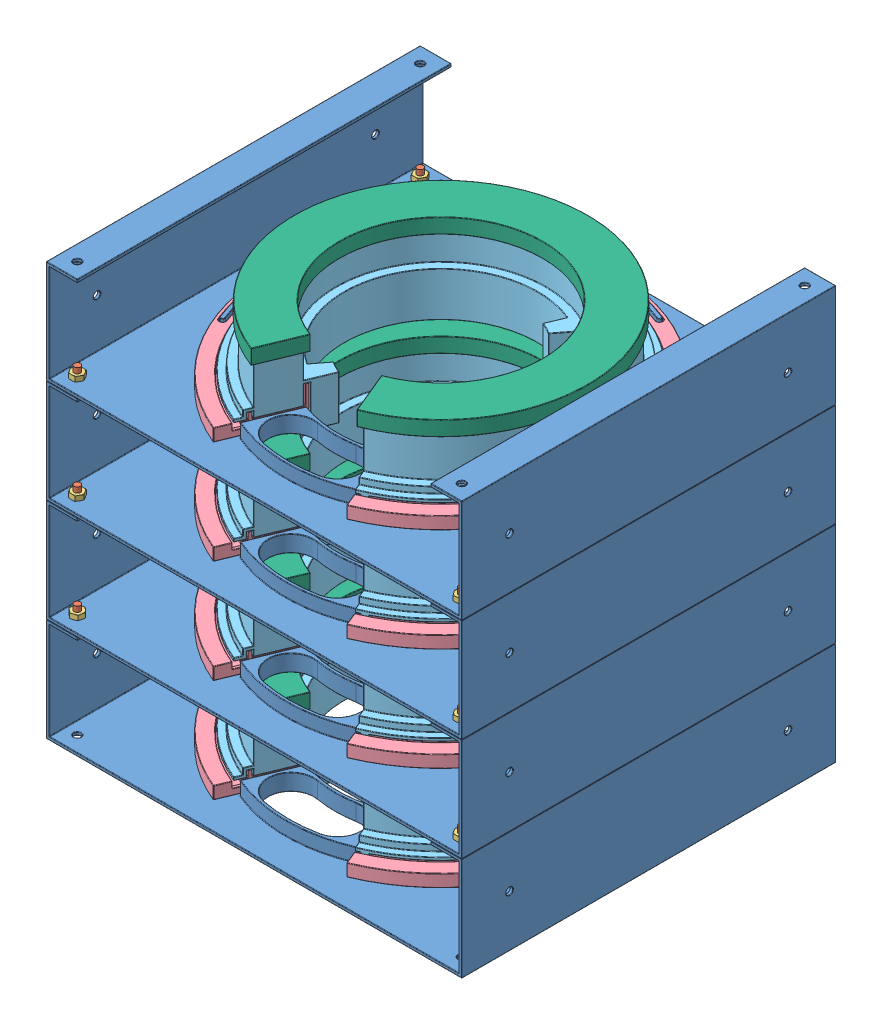
SolidWorks assembly Gavetas, configuration Valor predeterminado. Lengths in mm.
Overall size (200 201.3 180).
44 component instances, 6 part files, 69 mates.
Components (placement in the parent):
- CD-Gaveta-1: CD-Gaveta [Valor predeterminado] at (171.1976 -7.978 102.2527) x (1 0 0) z (0 1 0) size (200 180 49.7)
- CD-Gaveta-2: CD-Gaveta [Valor predeterminado] at (171.1976 41.722 102.2527) x (1 0 0) z (0 1 0) size (200 180 49.7)
- CD-Gaveta-3: CD-Gaveta [Valor predeterminado] at (171.1976 91.422 102.2527) x (1 0 0) z (0 1 0) size (200 180 49.7)
- CD-Gaveta-4: CD-Gaveta [Valor predeterminado] at (171.1976 141.122 102.2527) x (1 0 0) z (0 1 0) size (200 180 49.7)
- M3x8-1: M3x8 [Default] at (263.6976 89.922 184.7527) x (0 1 0) z (1 0 0) size (10.37 5.6 5.6)
- M3x8-2: M3x8 [Default] at (263.6976 89.922 19.7527) x (0 1 0) z (0 0 1) size (10.37 5.6 5.6)
- M3x8-3: M3x8 [Default] at (78.6976 40.222 184.7527) x (0 1 0) z (0 0 1) size (10.37 5.6 5.6)
- M3x8-4: M3x8 [Default] at (78.6976 89.922 184.7527) x (0 1 0) z (0 0 1) size (10.37 5.6 5.6)
- M3x8-5: M3x8 [Default] at (78.6976 89.922 19.7527) x (0 1 0) z (0 0 1) size (10.37 5.6 5.6)
- M3x8-6: M3x8 [Default] at (263.6976 40.222 19.7527) x (0 1 0) z (0 0 1) size (10.37 5.6 5.6)
- M3x8-7: M3x8 [Default] at (78.6976 40.222 19.7527) x (0 1 0) z (0 0 1) size (10.37 5.6 5.6)
- M3x8-8: M3x8 [Default] at (263.6976 40.222 184.7527) x (0 1 0) z (0 0 1) size (10.37 5.6 5.6)
- M3x8-9: M3x8 [Default] at (78.6976 139.622 19.7527) x (0 1 0) z (0 0 1) size (10.37 5.6 5.6)
- M3x8-10: M3x8 [Default] at (78.6976 139.622 184.7527) x (0 1 0) z (0 0 1) size (10.37 5.6 5.6)
- M3x8-11: M3x8 [Default] at (263.6976 139.622 184.7527) x (0 1 0) z (0 0 1) size (10.37 5.6 5.6)
- M3x8-12: M3x8 [Default] at (263.6976 139.622 19.7527) x (0 1 0) z (0 0 1) size (10.37 5.6 5.6)
- Porca M3-1: Porca M3 [Default] at (78.6976 92.922 184.7527) x (0 1 0) z (0 0 1) size (2.41 6.36 6.36)
- Porca M3-2: Porca M3 [Default] at (78.6976 142.622 184.7527) x (0 1 0) z (0 0 1) size (2.41 6.36 6.36)
- Porca M3-3: Porca M3 [Default] at (78.6976 43.222 184.7527) x (0 1 0) z (0.30223 0 0.953235) size (2.41 6.36 6.36)
- Porca M3-4: Porca M3 [Default] at (263.6976 92.922 184.7527) x (0 1 0) z (0.097704 0 0.995215) size (2.41 6.36 6.36)
- Porca M3-5: Porca M3 [Default] at (263.6976 142.622 184.7527) x (0 1 0) z (-0.795586 0 0.605841) size (2.41 6.36 6.36)
- Porca M3-6: Porca M3 [Default] at (263.6976 43.222 184.7527) x (0 1 0) z (0 0 1) size (2.41 6.36 6.36)
- Porca M3-7: Porca M3 [Default] at (78.6976 92.922 19.7527) x (0 1 0) z (0 0 1) size (2.41 6.36 6.36)
- Porca M3-8: Porca M3 [Default] at (78.6976 43.222 19.7527) x (0 1 0) z (0 0 1) size (2.41 6.36 6.36)
- Porca M3-9: Porca M3 [Default] at (78.6976 142.622 19.7527) x (0 1 0) z (0 0 1) size (2.41 6.36 6.36)
- Porca M3-10: Porca M3 [Default] at (263.6976 92.922 19.7527) x (0 1 0) z (-0.039427 0 0.999222) size (2.41 6.36 6.36)
- Porca M3-11: Porca M3 [Default] at (263.6976 43.222 19.7527) x (0 1 0) z (0 0 1) size (2.41 6.36 6.36)
- Porca M3-12: Porca M3 [Default] at (263.6976 142.622 19.7527) x (0 1 0) z (0 0 1) size (2.41 6.36 6.36)
- Case Montada-1: Case Montada [Valor predeterminado] at (178.8272 -18.9613 91.8282) x (1 0 0) z (0 1 0) size (167.75 161.29 41.2)
  - CD-Fixo Inferior-1: CD-Fixo Inferior [Valor predeterminado] at (-7.6296 -10.4244 160.0833) size (167.75 161.29 19.33)
  - CD-Movel-1: CD-Movel [Valor predeterminado] at (-7.6296 -10.4244 159.5833) size (152.75 146.86 40)
  - CD-Tampa-1: CD-Tampa [Valor predeterminado] at (-7.6296 -10.4244 159.0833) size (141.4 136.58 7.2)
- Case Montada-2: Case Montada [Valor predeterminado] at (178.8272 -68.6613 91.8282) x (1 0 0) z (0 1 0) size (167.75 161.29 41.2)
  - CD-Fixo Inferior-1: CD-Fixo Inferior [Valor predeterminado] at (-7.6296 -10.4244 160.0833) size (167.75 161.29 19.33)
  - CD-Movel-1: CD-Movel [Valor predeterminado] at (-7.6296 -10.4244 159.5833) size (152.75 146.86 40)
  - CD-Tampa-1: CD-Tampa [Valor predeterminado] at (-7.6296 -10.4244 159.0833) size (141.4 136.58 7.2)
- Case Montada-3: Case Montada [Valor predeterminado] at (178.8272 -118.3613 91.8282) x (1 0 0) z (0 1 0) size (167.75 161.29 41.2)
  - CD-Fixo Inferior-1: CD-Fixo Inferior [Valor predeterminado] at (-7.6296 -10.4244 160.0833) size (167.75 161.29 19.33)
  - CD-Movel-1: CD-Movel [Valor predeterminado] at (-7.6296 -10.4244 159.5833) size (152.75 146.86 40)
  - CD-Tampa-1: CD-Tampa [Valor predeterminado] at (-7.6296 -10.4244 159.0833) size (141.4 136.58 7.2)
- Case Montada-4: Case Montada [Valor predeterminado] at (178.8272 -168.0613 91.8282) x (1 0 0) z (0 1 0) size (167.75 161.29 41.2)
  - CD-Fixo Inferior-1: CD-Fixo Inferior [Valor predeterminado] at (-7.6296 -10.4244 160.0833) size (167.75 161.29 19.33)
  - CD-Movel-1: CD-Movel [Valor predeterminado] at (-7.6296 -10.4244 159.5833) size (152.75 146.86 40)
  - CD-Tampa-1: CD-Tampa [Valor predeterminado] at (-7.6296 -10.4244 159.0833) size (141.4 136.58 7.2)
Mates (geometry in assembly coordinates):
- Coincidente11: coincident aligned: plane of M3x8-6 through (261.3976 40.222 19.7527) normal (0 1 0); plane of M3x8-8 through (261.3976 40.222 184.7527) normal (0 1 0)
- Coincidente12: coincident aligned: plane of M3x8-6 through (261.3976 40.222 19.7527) normal (0 1 0); plane of M3x8-7 through (76.3976 40.222 19.7527) normal (0 1 0)
- Coincidente13: coincident aligned: plane of M3x8-3 through (76.3976 40.222 184.7527) normal (0 1 0); plane of M3x8-7 through (76.3976 40.222 19.7527) normal (0 1 0)
- Concêntrico1: concentric anti-aligned: cylinder of M3x8-3 through (78.6976 44.722 184.7527) axis (0 -1 0) radius 1.5; cylinder of CD-Gaveta-1 through (78.6976 -158.278 184.7527) axis (0 1 0) radius 1.75
- Concêntrico2: concentric anti-aligned: cylinder of M3x8-7 through (78.6976 44.722 19.7527) axis (0 -1 0) radius 1.5; cylinder of CD-Gaveta-1 through (78.6976 -158.278 19.7527) axis (0 1 0) radius 1.75
- Concêntrico3: concentric anti-aligned: cylinder of M3x8-6 through (263.6976 44.722 19.7527) axis (0 -1 0) radius 1.5; cylinder of CD-Gaveta-1 through (263.6976 -158.278 19.7527) axis (0 1 0) radius 1.75
- Concêntrico4: concentric anti-aligned: cylinder of M3x8-8 through (263.6976 44.722 184.7527) axis (0 -1 0) radius 1.5; cylinder of CD-Gaveta-1 through (263.6976 -158.278 184.7527) axis (0 1 0) radius 1.75
- Coincidente14: coincident anti-aligned: plane of CD-Gaveta-1 through (171.1976 40.222 102.2527) normal (0 -1 0); plane of M3x8-8 through (261.3976 40.222 184.7527) normal (0 1 0)
- Coincidente15: coincident: plane of M3x8-1 through (263.6976 89.922 187.0527) normal (0 1 0); plane of M3x8-2 through (261.3976 89.922 19.7527) normal (0 1 0)
- Coincidente16: coincident aligned: plane of M3x8-2 through (261.3976 89.922 19.7527) normal (0 1 0); plane of M3x8-5 through (76.3976 89.922 19.7527) normal (0 1 0)
- Coincidente17: coincident aligned: plane of M3x8-2 through (261.3976 89.922 19.7527) normal (0 1 0); plane of M3x8-4 through (76.3976 89.922 184.7527) normal (0 1 0)
- Concêntrico5: concentric anti-aligned: cylinder of M3x8-4 through (78.6976 94.422 184.7527) axis (0 -1 0) radius 1.5; cylinder of CD-Gaveta-2 through (78.6976 -108.578 184.7527) axis (0 1 0) radius 1.75
- Concêntrico6: concentric anti-aligned: cylinder of M3x8-5 through (78.6976 94.422 19.7527) axis (0 -1 0) radius 1.5; cylinder of CD-Gaveta-2 through (78.6976 -108.578 19.7527) axis (0 1 0) radius 1.75
- Concêntrico7: concentric anti-aligned: cylinder of M3x8-2 through (263.6976 94.422 19.7527) axis (0 -1 0) radius 1.5; cylinder of CD-Gaveta-2 through (263.6976 -108.578 19.7527) axis (0 1 0) radius 1.75
- Concêntrico8: concentric anti-aligned: cylinder of M3x8-1 through (263.6976 94.422 184.7527) axis (0 -1 0) radius 1.5; cylinder of CD-Gaveta-2 through (263.6976 -108.578 184.7527) axis (0 1 0) radius 1.75
- Coincidente18: coincident anti-aligned: plane of CD-Gaveta-2 through (171.1976 89.922 102.2527) normal (0 -1 0); plane of M3x8-1 through (263.6976 89.922 187.0527) normal (0 1 0)
- Coincidente19: coincident aligned: plane of M3x8-9 through (76.3976 139.622 19.7527) normal (0 1 0); plane of M3x8-10 through (76.3976 139.622 184.7527) normal (0 1 0)
- Coincidente20: coincident aligned: plane of M3x8-10 through (76.3976 139.622 184.7527) normal (0 1 0); plane of M3x8-11 through (261.3976 139.622 184.7527) normal (0 1 0)
- Coincidente21: coincident aligned: plane of M3x8-11 through (261.3976 139.622 184.7527) normal (0 1 0); plane of M3x8-12 through (261.3976 139.622 19.7527) normal (0 1 0)
- Concêntrico9: concentric anti-aligned: cylinder of M3x8-9 through (78.6976 144.122 19.7527) axis (0 -1 0) radius 1.5; cylinder of CD-Gaveta-3 through (78.6976 -58.878 19.7527) axis (0 1 0) radius 1.75
- Concêntrico10: concentric anti-aligned: cylinder of M3x8-10 through (78.6976 144.122 184.7527) axis (0 -1 0) radius 1.5; cylinder of CD-Gaveta-3 through (78.6976 -58.878 184.7527) axis (0 1 0) radius 1.75
- Concêntrico11: concentric anti-aligned: cylinder of M3x8-11 through (263.6976 144.122 184.7527) axis (0 -1 0) radius 1.5; cylinder of CD-Gaveta-3 through (263.6976 -58.878 184.7527) axis (0 1 0) radius 1.75
- Concêntrico12: concentric anti-aligned: cylinder of M3x8-12 through (263.6976 144.122 19.7527) axis (0 -1 0) radius 1.5; cylinder of CD-Gaveta-3 through (263.6976 -58.878 19.7527) axis (0 1 0) radius 1.75
- Coincidente23: coincident anti-aligned: plane of CD-Gaveta-3 through (171.1976 139.622 102.2527) normal (0 -1 0); plane of M3x8-11 through (261.3976 139.622 184.7527) normal (0 1 0)
- Concêntrico13: concentric aligned: cylinder of Porca M3-1 through (78.6976 95.322 184.7527) axis (0 -1 0) radius 1.2295; cylinder of Porca M3-2 through (78.6976 145.022 184.7527) axis (0 -1 0) radius 1.2295
- Concêntrico14: concentric aligned: cylinder of Porca M3-2 through (78.6976 145.022 184.7527) axis (0 -1 0) radius 1.2295; cylinder of Porca M3-3 through (78.6976 45.622 184.7527) axis (0 -1 0) radius 1.2295
- Coincidente24: coincident aligned: plane of Porca M3-1 through (75.9476 95.322 184.7527) normal (0 1 0); plane of Porca M3-4 through (260.9608 95.322 185.0213) normal (0 1 0)
- Concêntrico15: concentric aligned: cylinder of Porca M3-5 through (263.6976 145.022 184.7527) axis (0 -1 0) radius 1.2295; cylinder of Porca M3-6 through (263.6976 45.622 184.7527) axis (0 -1 0) radius 1.2295
- Concêntrico16: concentric aligned: cylinder of Porca M3-4 through (263.6976 95.322 184.7527) axis (0 -1 0) radius 1.2295; cylinder of Porca M3-6 through (263.6976 45.622 184.7527) axis (0 -1 0) radius 1.2295
- Coincidente25: coincident aligned: plane of Porca M3-3 through (76.0762 45.622 185.5838) normal (0 1 0); plane of Porca M3-6 through (260.9476 45.622 184.7527) normal (0 1 0)
- Coincidente26: coincident aligned: plane of Porca M3-2 through (75.9476 145.022 184.7527) normal (0 1 0); plane of Porca M3-5 through (262.0315 145.022 182.5648) normal (0 1 0)
- Concêntrico17: concentric aligned: cylinder of Porca M3-8 through (78.6976 45.622 19.7527) axis (0 -1 0) radius 1.2295; cylinder of Porca M3-9 through (78.6976 145.022 19.7527) axis (0 -1 0) radius 1.2295
- Concêntrico18: concentric aligned: cylinder of Porca M3-7 through (78.6976 95.322 19.7527) axis (0 -1 0) radius 1.2295; cylinder of Porca M3-9 through (78.6976 145.022 19.7527) axis (0 -1 0) radius 1.2295
- Concêntrico19: concentric aligned: cylinder of Porca M3-11 through (263.6976 45.622 19.7527) axis (0 -1 0) radius 1.2295; cylinder of Porca M3-12 through (263.6976 145.022 19.7527) axis (0 -1 0) radius 1.2295
- Concêntrico20: concentric aligned: cylinder of Porca M3-10 through (263.6976 95.322 19.7527) axis (0 -1 0) radius 1.2295; cylinder of Porca M3-12 through (263.6976 145.022 19.7527) axis (0 -1 0) radius 1.2295
- Coincidente27: coincident aligned: plane of Porca M3-5 through (262.0315 145.022 182.5648) normal (0 1 0); plane of Porca M3-9 through (75.9476 145.022 19.7527) normal (0 1 0)
- Coincidente28: coincident aligned: plane of Porca M3-9 through (75.9476 145.022 19.7527) normal (0 1 0); plane of Porca M3-12 through (260.9476 145.022 19.7527) normal (0 1 0)
- Coincidente29: coincident aligned: plane of Porca M3-6 through (260.9476 45.622 184.7527) normal (0 1 0); plane of Porca M3-8 through (75.9476 45.622 19.7527) normal (0 1 0)
- Coincidente30: coincident aligned: plane of Porca M3-8 through (75.9476 45.622 19.7527) normal (0 1 0); plane of Porca M3-11 through (260.9476 45.622 19.7527) normal (0 1 0)
- Coincidente31: coincident aligned: plane of Porca M3-4 through (260.9608 95.322 185.0213) normal (0 1 0); plane of Porca M3-7 through (75.9476 95.322 19.7527) normal (0 1 0)
- Coincidente32: coincident aligned: plane of Porca M3-7 through (75.9476 95.322 19.7527) normal (0 1 0); plane of Porca M3-10 through (260.9497 95.322 19.6442) normal (0 1 0)
- Concêntrico21: concentric aligned: cylinder of M3x8-10 through (78.6976 144.122 184.7527) axis (0 -1 0) radius 1.5; cylinder of Porca M3-2 through (78.6976 145.022 184.7527) axis (0 -1 0) radius 1.2295
- Concêntrico22: concentric aligned: cylinder of M3x8-11 through (263.6976 144.122 184.7527) axis (0 -1 0) radius 1.5; cylinder of Porca M3-5 through (263.6976 145.022 184.7527) axis (0 -1 0) radius 1.2295
- Concêntrico23: concentric aligned: cylinder of M3x8-9 through (78.6976 144.122 19.7527) axis (0 -1 0) radius 1.5; cylinder of Porca M3-9 through (78.6976 145.022 19.7527) axis (0 -1 0) radius 1.2295
- Concêntrico24: concentric aligned: cylinder of M3x8-12 through (263.6976 144.122 19.7527) axis (0 -1 0) radius 1.5; cylinder of Porca M3-12 through (263.6976 145.022 19.7527) axis (0 -1 0) radius 1.2295
- Coincidente33: coincident anti-aligned: plane of CD-Gaveta-4 through (171.1976 142.622 102.2527) normal (0 1 0); plane of Porca M3-5 through (263.6976 142.622 184.7527) normal (0 -1 0)
- Coincidente34: coincident anti-aligned: plane of CD-Gaveta-3 through (171.1976 92.922 102.2527) normal (0 1 0); plane of Porca M3-1 through (78.6976 92.922 184.7527) normal (0 -1 0)
- Coincidente35: coincident anti-aligned: plane of CD-Gaveta-2 through (171.1976 43.222 102.2527) normal (0 1 0); plane of Porca M3-3 through (78.6976 43.222 184.7527) normal (0 -1 0)
- Concêntrico25: concentric aligned: cylinder of Case Montada-1/CD-Movel-1 through (171.1976 159.9554 102.2527) axis (0 -1 0) radius 46.5; cylinder of Case Montada-2/CD-Movel-1 through (171.1976 110.2554 102.2527) axis (0 -1 0) radius 46.5
- Concêntrico26: concentric aligned: cylinder of Case Montada-2/CD-Movel-1 through (171.1976 110.2554 102.2527) axis (0 -1 0) radius 46.5; cylinder of Case Montada-3/CD-Movel-1 through (171.1976 60.5554 102.2527) axis (0 -1 0) radius 46.5
- Concêntrico27: concentric aligned: cylinder of Case Montada-3/CD-Movel-1 through (171.1976 60.5554 102.2527) axis (0 -1 0) radius 46.5; cylinder of Case Montada-4/CD-Movel-1 through (171.1976 10.8554 102.2527) axis (0 -1 0) radius 46.5
- Concêntrico28: concentric aligned: cylinder of Case Montada-1/CD-Movel-1 through (171.1976 159.9554 102.2527) axis (0 -1 0) radius 46.5; cylinder of CD-Gaveta-4 through (171.1976 147.122 102.2527) axis (0 -1 0) radius 52.5
- Coincidente36: coincident aligned: plane of Case Montada-3/CD-Movel-1 through (171.1976 265.1721 102.2527) normal (0.92388 0 0.382683); plane of Case Montada-4/CD-Movel-1 through (171.1976 215.4721 102.2527) normal (0.92388 0 0.382683)
- Coincidente37: coincident aligned: plane of Case Montada-3/CD-Movel-1 through (171.1976 265.1721 102.2527) normal (0.92388 0 0.382683); plane of Case Montada-2/CD-Movel-1 through (171.1976 314.8721 102.2527) normal (0.92388 0 0.382683)
- Coincidente38: coincident aligned: plane of Case Montada-2/CD-Movel-1 through (171.1976 314.8721 102.2527) normal (0.92388 0 0.382683); plane of Case Montada-1/CD-Movel-1 through (171.1976 364.5721 102.2527) normal (0.92388 0 0.382683)
- Concêntrico29: concentric aligned: cylinder of Case Montada-4/CD-Movel-1 through (171.1976 10.8554 102.2527) axis (0 -1 0) radius 46.5; circle of CD-Gaveta-1
- Coincidente45: coincident aligned: plane of CD-Gaveta-3 through (271.1976 92.922 192.2527) normal (1 0 0); plane of CD-Gaveta-4 through (271.1976 142.622 192.2527) normal (1 0 0)
- Coincidente46: coincident aligned: plane of CD-Gaveta-2 through (271.1976 43.222 192.2527) normal (1 0 0); plane of CD-Gaveta-3 through (271.1976 92.922 192.2527) normal (1 0 0)
- Coincidente47: coincident aligned: plane of CD-Gaveta-1 through (271.1976 -6.478 192.2527) normal (1 0 0); plane of CD-Gaveta-2 through (271.1976 43.222 192.2527) normal (1 0 0)
- Coincidente48: coincident aligned: plane of CD-Gaveta-3 through (71.1976 92.922 192.2527) normal (0 0 1); plane of CD-Gaveta-4 through (71.1976 142.622 192.2527) normal (0 0 1)
- Coincidente49: coincident aligned: plane of CD-Gaveta-2 through (71.1976 43.222 192.2527) normal (0 0 1); plane of CD-Gaveta-3 through (71.1976 92.922 192.2527) normal (0 0 1)
- Coincidente50: coincident anti-aligned: plane of CD-Gaveta-3 through (171.1976 141.122 102.2527) normal (0 1 0); plane of CD-Gaveta-4 through (171.1976 141.122 102.2527) normal (0 -1 0)
- Coincidente51: coincident anti-aligned: plane of CD-Gaveta-2 through (171.1976 91.422 102.2527) normal (0 1 0); plane of CD-Gaveta-3 through (171.1976 91.422 102.2527) normal (0 -1 0)
- Coincidente52: coincident anti-aligned: plane of CD-Gaveta-1 through (171.1976 41.722 102.2527) normal (0 1 0); plane of CD-Gaveta-2 through (171.1976 41.722 102.2527) normal (0 -1 0)
- Concêntrico30: concentric aligned: circle of CD-Gaveta-4; cylinder of Case Montada-1/CD-Fixo Inferior-1 through (96.1019 144.622 132.2759) axis (0 -1 0) radius 1.5
- Coincidente54: coincident aligned: plane of CD-Gaveta-4 through (171.1976 149.122 99.2527) normal (0 1 0); plane of Case Montada-1/CD-Fixo Inferior-1 through (171.1976 149.122 102.2527) normal (0 1 0)
- Coincidente55: coincident aligned: plane of CD-Gaveta-3 through (171.1976 99.422 99.2527) normal (0 1 0); plane of Case Montada-2/CD-Fixo Inferior-1 through (171.1976 99.422 102.2527) normal (0 1 0)
- Coincidente56: coincident aligned: plane of CD-Gaveta-2 through (171.1976 49.722 99.2527) normal (0 1 0); plane of Case Montada-3/CD-Fixo Inferior-1 through (171.1976 49.722 102.2527) normal (0 1 0)
- Coincidente57: coincident aligned: plane of CD-Gaveta-1 through (171.1976 0.022 99.2527) normal (0 1 0); plane of Case Montada-4/CD-Fixo Inferior-1 through (171.1976 0.022 102.2527) normal (0 1 0)
